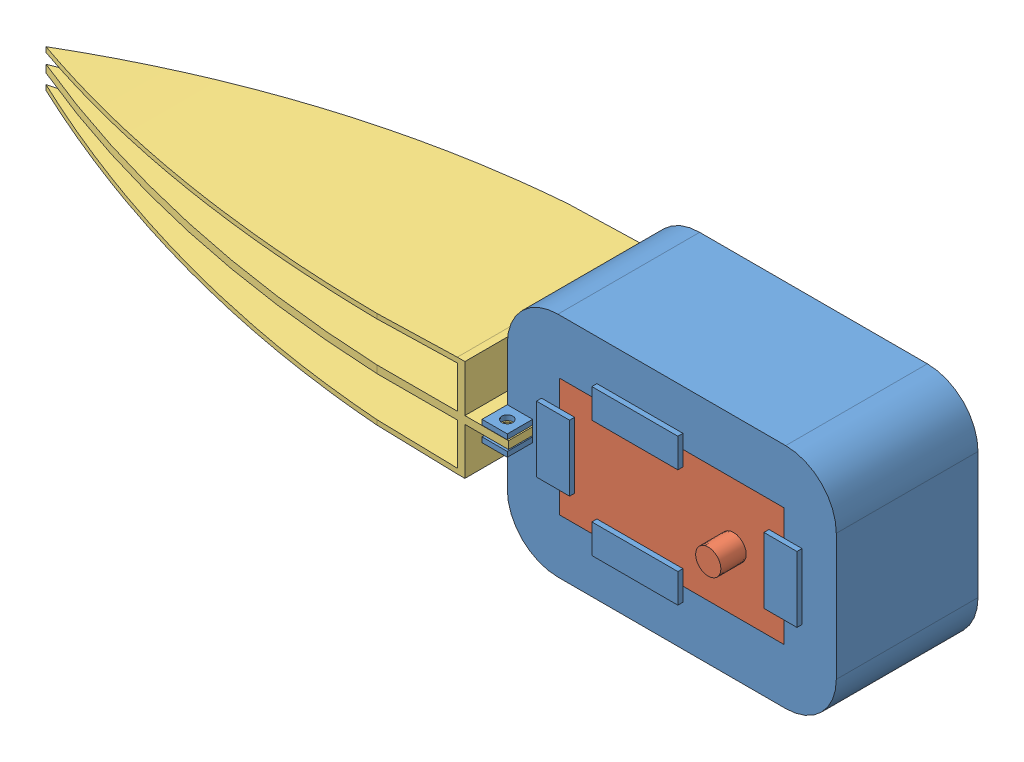
SolidWorks assembly link6, configuration 預設. Lengths in mm.
Overall size (170.1 45 38.21).
3 component instances, 3 part files, 12 mates.
Components (placement in the parent):
- bus2_tail-2: bus2_tail [預設] at (14.9347 0 -13.5) size (65 45 38)
- bus_servo-2: bus_servo [預設] at (7.4478 11.4931 14.5) x (1 0 0) z (0 1 0) size (44.4 38 23.4)
- bus_final_tail-1: bus_final_tail [預設] at (-49.0906 0 -0.2306) x (-1 0 0.00071) z (0 1 0) size (110.1 38.13 25.31)
Mates (geometry in assembly coordinates):
- 平行相距1: distance = 18.5 mm: plane of ? through (-0.1 0 18.5) normal (0 0 -1); plane of assembly through (0 0 0) normal (0 0 1)
- 平行相距2: distance = 12 mm: plane of assembly through (0 0 0) normal (0 1 0); plane of ? through (33.9 12 -20) normal (0 1 0)
- 平行相距3: distance = 7 mm: plane of assembly through (0 0 0) normal (1 0 0); plane of ? through (7 1.05 -20) normal (-1 0 0)
- 重合/共線/共點6: coincident: plane of bus_servo-2 through (9.7 -11.7 -13.5) normal (1 0 0); plane of bus2_tail-2 through (9.7 11.7 25.5) normal (-1 0 0)
- 重合/共線/共點7: coincident: plane of bus2_tail-2 through (-34.7 11.7 25.5) normal (0 -1 0); plane of bus_servo-2 through (-34.7 11.7 -13.5) normal (0 1 0)
- 重合/共線/共點8: coincident: plane of bus2_tail-2 through (14.9347 0 -13.5) normal (0 0 -1); plane of bus_servo-2 through (7.4478 11.4931 -13.5) normal (0 0 -1)
- 平行相距6: distance = 45 mm: plane of assembly; plane of bus2_tail-2 through (-45 22.5 14.5) normal (-1 0 0)
- 平行相距7: distance = 13.5 mm: plane of assembly; plane of bus2_tail-2 through (14.9347 0 -13.5) normal (0 0 -1)
- 平行相距8: distance = 22.5 mm: plane of assembly; plane of bus2_tail-2 through (-45 -22.5 14.5) normal (0 -1 0)
- 同軸心1: concentric: cylinder of bus2_tail-2 through (-42.5 5 17) axis (0 -1 0) radius 1.1; cylinder of bus_final_tail-1 through (-42.5 -0.75 17) axis (0 1 0) radius 1.1
- 同軸心2: concentric: cylinder of bus2_tail-2 through (-42.5 5 -16) axis (0 -1 0) radius 1.1; cylinder of bus_final_tail-1 through (-42.5 -0.75 -16) axis (0 1 0) radius 1.1
- 平行相距9: distance = 0.25 mm: plane of bus2_tail-2 through (14.9347 1 -13.5) normal (0 -1 0); plane of bus_final_tail-1 through (-49.0906 0.75 -0.2306) normal (0 1 0)
